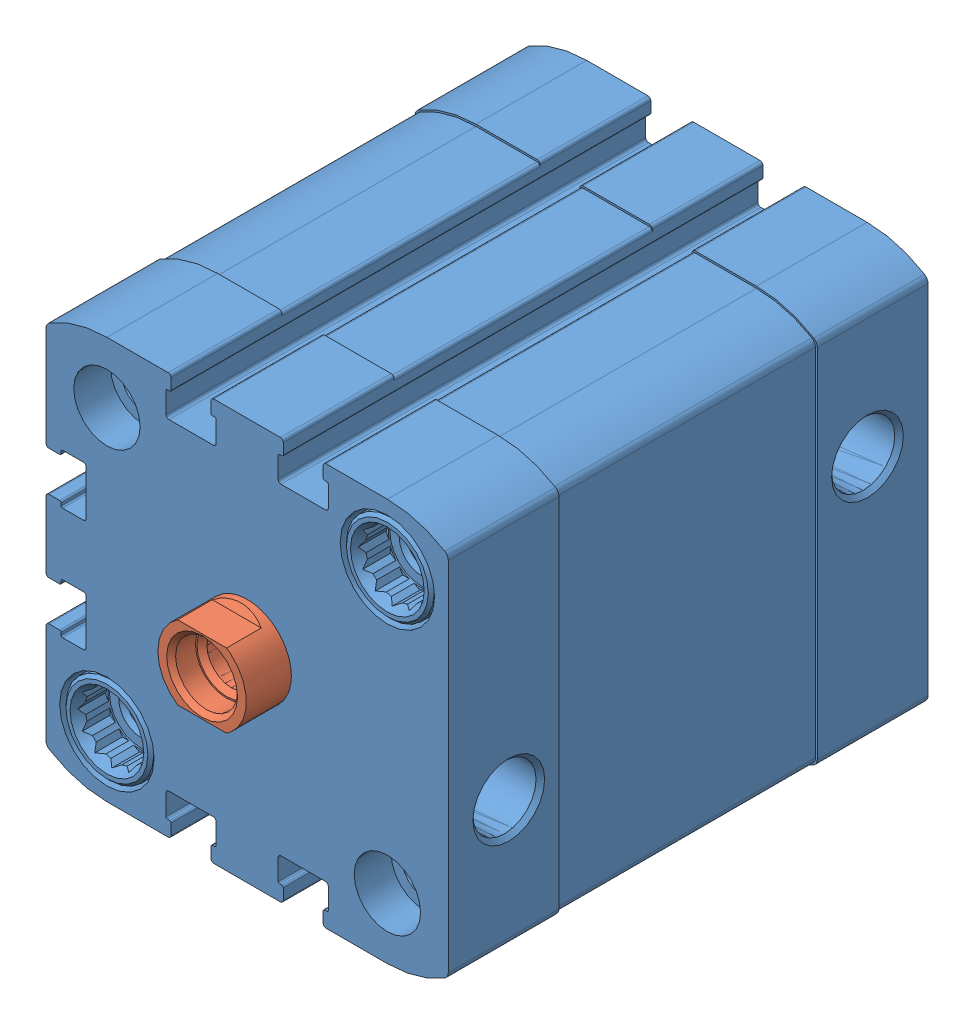
SolidWorks assembly 536302_ADN_40_20_I_P_A____asm_0_, configuration Standard. Lengths in mm.
Overall size (54.5 54.5 71.1).
2 component instances, 2 part files, 2 mates.
Components (placement in the parent):
- 536288_ADN_20_P____Z_-1: 536288_ADN_20_P____Z_ [Standard] at origin size (54.5 54.5 65)
- 536288_ADN_20_P_I__KS_-1: 536288_ADN_20_P_I__KS_ [Standard] x (0 0 -1) z (-1 0 0) size (54.7 40 40)
Mates (geometry in assembly coordinates):
- Deckungsgleich1: coincident anti-aligned: line of 536288_ADN_20_P____Z_-1 through (0 0 80.9) axis (0 0 -1); line of 536288_ADN_20_P_I__KS_-1 through (0 0 -80.9) axis (0 0 1)
- Winkel3: planar angle = 0 rad aligned: plane of 536288_ADN_20_P_I__KS_-1 through (0 0 0) normal (1 0 0); plane of 536288_ADN_20_P____Z_-1 through (0 0 0) normal (1 0 0)
